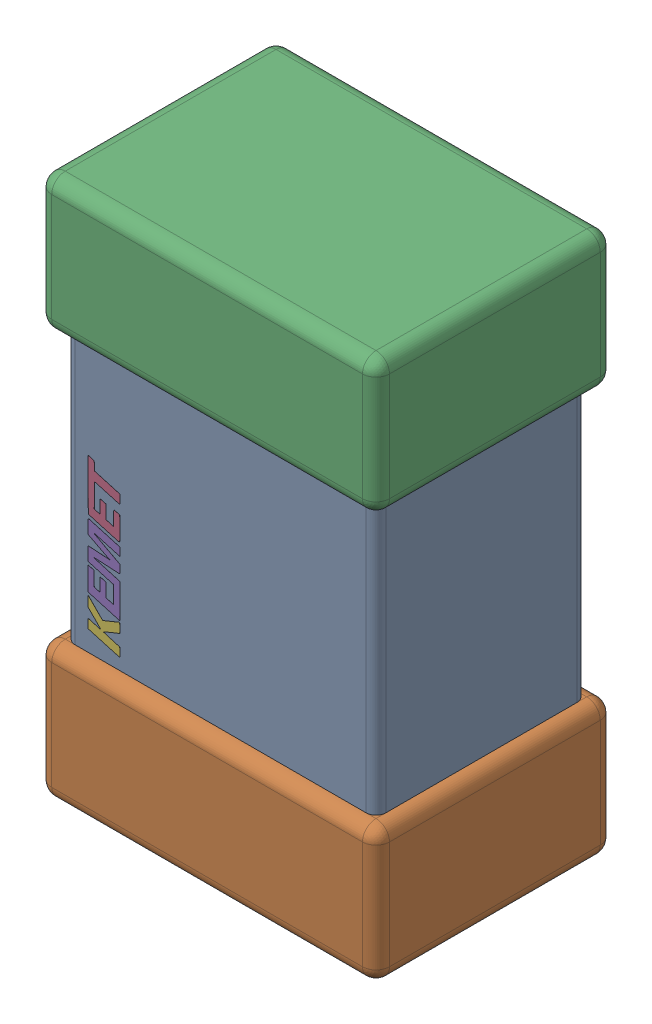
SolidWorks assembly C6.step, configuration Default. Lengths in mm.
Overall size (1.25 2 0.88).
3 component instances, 3 part files, 0 mates.
Components (placement in the parent):
- Cap_KEMET_C0805C472J3HAC_eec.step-1: Cap_KEMET_C0805C472J3HAC_eec.step [Default] at (35.516 65.924 0) x (0 1 0) z (0 0 1) size (1 1.15 0.78)
- Cap_KEMET_C0805C472J3HAC_eec-7.step-1: Cap_KEMET_C0805C472J3HAC_eec-7.step [Default] at (35.516 65.924 0) x (0 1 0) z (0 0 1) size (2 1.25 0.88)
- Cap_KEMET_C0805C472J3HAC_eec-8.step-1: Cap_KEMET_C0805C472J3HAC_eec-8.step [Default] at (35.516 65.924 0) x (0 1 0) z (0 0 1) size (0.59 0.12 0)
